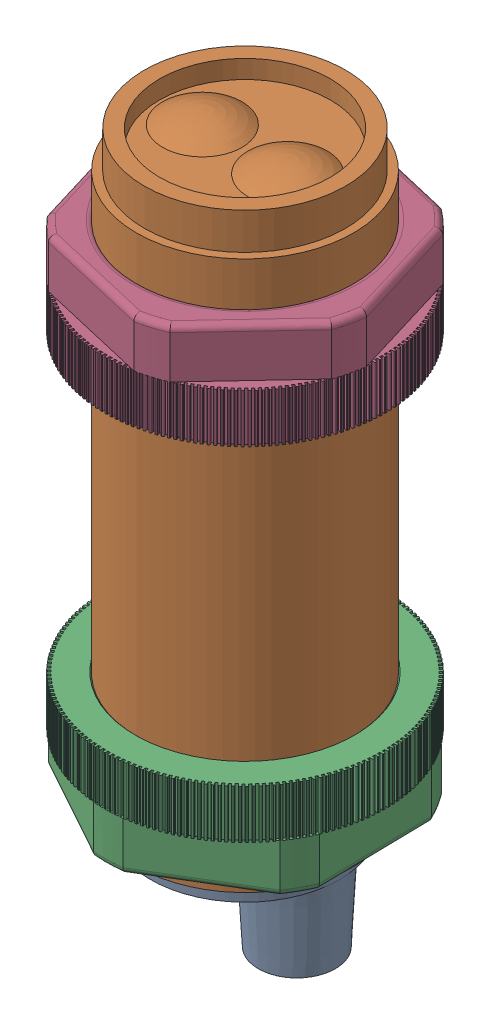
SolidWorks assembly photoelectric sensor, configuration Default. Lengths in mm.
Overall size (32.51 56 32.51).
3 component instances, 2 part files, 2 mates.
Components (placement in the parent):
- sensor photo elektrik-1: sensor photo elektrik [Default] at origin size (17.8 56 17.8)
- sensor clamp-1: sensor clamp [Default] at (0 1.3869 0) x (0.999825 0 -0.018696) z (0.018696 0 0.999825) size (23 8.03 23)
- sensor clamp-2: sensor clamp [Default] at (0 41.4925 0) x (-0.729747 0 -0.683717) z (-0.683717 0 0.729747) size (23 8.03 23)
Mates (geometry in assembly coordinates):
- Concentric1: concentric aligned: cylinder of sensor photo elektrik-1 through (0 48 0) axis (0 -1 0) radius 8.25; cylinder of sensor clamp-1 through (0 5.3869 0) axis (0 -1 0) radius 8.5
- Concentric2: concentric aligned: circle of sensor photo elektrik-1; cylinder of sensor clamp-2 through (0 37.4925 0) axis (0 1 0) radius 8.5
